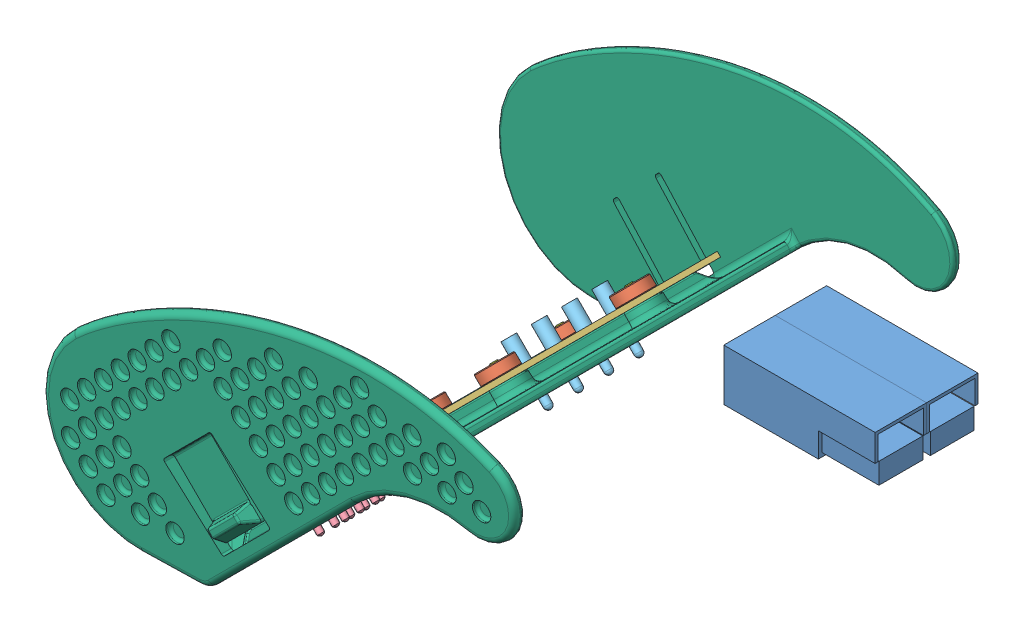
SolidWorks assembly AU-SK-2-000669, configuration Default. Lengths in mm.
Overall size (144.45 131.85 147.55).
25 component instances, 9 part files, 24 mates.
Components (placement in the parent):
- AU-SK-100-000494-1: AU-SK-100-000494 [Default] at (-11.8083 -137.0825 45.0576) size (144.45 105.44 132.78)
  - AU-SK-1-000249-1: AU-SK-1-000249 [Default] at (90.6703 82.4308 -22.9944) x (0 0 1) z (-1 -0.00005 0) size (17.27 8.64 25.4)
  - AU-SK-1-000615-1: AU-SK-1-000615 [Default] at (55.9151 53.7792 -42.3665) size (54 22.81 0.51)
  - AU-SK-1-000614-1: AU-SK-1-000614 [Default] at (56.8933 45.7752 -44.5778) size (52.76 21.32 0.51)
  - AU-SK-1-000592-1: AU-SK-1-000592 [95117A411] at (18.1101 50.4596 -56.7407) x (0.5 0.5 0.707107) z (-0.707107 0.707107 0) size (5.59 5.59 3.59)
  - AU-SK-1-000592-2: AU-SK-1-000592 [95117A411] at (6.4358 38.7852 -56.7407) x (0.5 0.5 0.707107) z (-0.707107 0.707107 0) size (5.59 5.59 3.59)
  - AU-SK-1-000592-3: AU-SK-1-000592 [95117A411] at (18.1101 50.4596 -34.0839) x (0.5 0.5 0.707107) z (-0.707107 0.707107 0) size (5.59 5.59 3.59)
  - AU-SK-1-000592-4: AU-SK-1-000592 [95117A411] at (6.4358 38.7852 -34.0839) x (0.5 0.5 0.707107) z (-0.707107 0.707107 0) size (5.59 5.59 3.59)
  - AU-SK-1-000592-5: AU-SK-1-000592 [95117A411] at (18.1101 50.4596 -11.4271) x (0.5 0.5 0.707107) z (-0.707107 0.707107 0) size (5.59 5.59 3.59)
  - AU-SK-1-000592-6: AU-SK-1-000592 [95117A411] at (6.4358 38.7852 -11.4271) x (0.5 0.5 0.707107) z (-0.707107 0.707107 0) size (5.59 5.59 3.59)
  - AU-SK-2-000791-1: AU-SK-2-000791 [Default] at (29.3531 69.1902 -54.4746) size (81.07 81.07 132.78)
    - AU-SK-1-000449-1: AU-SK-1-000449 [Default] at (-82.5713 -93.6909 -83.1375) x (0 0 1) z (-0.707107 0.707107 0) size (132.78 113.86 0.79)
    - AU-SK-1-000590-1: AU-SK-1-000590 [Default] at (-11.8156 -27.4433 32.3933) x (0 0 -1) z (-0.707107 -0.707107 0) size (20.32 6.76 2.54)
    - AU-SK-1-000080-1: AU-SK-1-000080 [Default] at (-18.3223 -23.3313 -4.3851) x (0.658834 0.658834 -0.363148) z (-0.256784 -0.256784 -0.931732) size (3.81 9.91 3.81)
    - AU-SK-1-000080-2: AU-SK-1-000080 [Default] at (-18.3203 -23.3333 0.6949) x (-0.707107 -0.707107 0) z (0 0 1) size (3.81 9.91 3.81)
    - AU-SK-1-000080-3: AU-SK-1-000080 [Default] at (-18.3203 -23.3333 5.7749) x (-0.707107 -0.707107 0) z (0 0 1) size (3.81 9.91 3.81)
    - AU-SK-1-000080-4: AU-SK-1-000080 [Default] at (-18.3203 -23.3333 10.8549) x (-0.707107 -0.707107 0) z (0 0 1) size (3.81 9.91 3.81)
    - AU-SK-1-000590-2: AU-SK-1-000590 [Default] at (-16.0064 -31.6341 32.3933) x (0 0 -1) z (-0.707107 -0.707107 0) size (20.32 6.76 2.54)
- AU-SK-1-000474-1: AU-SK-1-000474 [Default] at (-3.9 -105.7731 10.9669) x (0 0 1) z (-0.707107 0.707107 0) size (87.74 80.21 52.37)
- AU-SK-1-000591-1: AU-SK-1-000591 [91253A078] at (6.1961 -86.5172 -11.6831) x (0.5 0.5 0.707107) z (-0.707107 0.707107 0) size (5 5 6.82)
- AU-SK-1-000591-2: AU-SK-1-000591 [91253A078] at (6.1961 -86.5172 33.6169) x (0.5 0.5 0.707107) z (-0.707107 0.707107 0) size (5 5 6.82)
- AU-SK-1-000591-3: AU-SK-1-000591 [91253A078] at (-5.4783 -98.1915 -11.6831) x (0.5 0.5 0.707107) z (-0.707107 0.707107 0) size (5 5 6.82)
- AU-SK-1-000591-4: AU-SK-1-000591 [91253A078] at (-5.4783 -98.1915 33.6169) x (0.5 0.5 0.707107) z (-0.707107 0.707107 0) size (5 5 6.82)
- AU-SK-1-000591-5: AU-SK-1-000591 [91253A078] at (-5.4348 -98.2349 10.9669) x (0.5 0.5 0.707107) z (-0.707107 0.707107 0) size (5 5 6.82)
- AU-SK-1-000591-6: AU-SK-1-000591 [91253A078] at (6.1961 -86.5172 10.9669) x (0.5 0.5 0.707107) z (-0.707107 0.707107 0) size (5 5 6.82)
Mates (geometry in assembly coordinates):
- Concentric3: concentric: circle of AU-SK-1-000474-1; circle of AU-SK-100-000494-1/AU-SK-2-000791-1/AU-SK-1-000080-1
- Coincident69: coincident: plane of AU-SK-1-000474-1 through (-6.5582 -103.1149 10.9669) normal (-0.707107 0.707107 0); plane of ? through (-31.2723 -127.8291 10.9669) normal (0.707107 -0.707107 0)
- Concentric19: concentric: circle of AU-SK-1-000474-1; circle of ?
- Concentric20: concentric: circle of AU-SK-1-000474-1; circle of ?
- Concentric21: concentric: circle of AU-SK-1-000474-1; circle of AU-SK-100-000494-1/AU-SK-2-000791-1/AU-SK-1-000590-1
- Parallel18: parallel: line of AU-SK-1-000474-1 through (4.9112 -94.7168 18.4559) axis (0 0 1); plane of AU-SK-100-000494-1/AU-SK-2-000791-1/AU-SK-1-000590-1 through (3.7536 -93.36 22.9763) normal (-0.707107 -0.707107 0)
- Concentric18: concentric: circle of AU-SK-100-000494-1/AU-SK-1-000592-1; circle of AU-SK-1-000591-1
- Distance10: distance = 0.127 mm: plane of AU-SK-1-000591-1 through (10.6862 -91.0073 -11.6831) normal (0.707107 -0.707107 0); plane of AU-SK-1-000474-1 through (20.8487 -81.0244 48.9399) normal (0.707107 -0.707107 0)
- Concentric22: concentric anti-aligned: circle of AU-SK-1-000474-1; circle of AU-SK-1-000591-6
- Concentric23: concentric aligned: circle of AU-SK-1-000591-2; circle of AU-SK-1-000474-1
- Concentric24: concentric anti-aligned: circle of AU-SK-1-000474-1; circle of AU-SK-1-000591-4
- Concentric25: concentric anti-aligned: circle of AU-SK-1-000474-1; circle of AU-SK-1-000591-5
- Concentric26: concentric anti-aligned: circle of AU-SK-1-000474-1; circle of AU-SK-1-000591-3
- Coincident70: coincident aligned: plane of AU-SK-1-000591-1 through (10.6862 -91.0073 -11.6831) normal (0.707107 -0.707107 0); plane of AU-SK-1-000591-6 through (10.6862 -91.0073 10.9669) normal (0.707107 -0.707107 0)
- Coincident71: coincident aligned: plane of AU-SK-1-000591-1 through (10.6862 -91.0073 -11.6831) normal (0.707107 -0.707107 0); plane of AU-SK-1-000591-2 through (10.6862 -91.0073 33.6169) normal (0.707107 -0.707107 0)
- Coincident72: coincident aligned: plane of AU-SK-1-000591-1 through (10.6862 -91.0073 -11.6831) normal (0.707107 -0.707107 0); plane of AU-SK-1-000591-3 through (-0.9881 -102.6816 -11.6831) normal (0.707107 -0.707107 0)
- Coincident73: coincident anti-aligned: plane of AU-SK-1-000591-1 through (10.6862 -91.0073 -11.6831) normal (0.707107 -0.707107 0); circle of AU-SK-1-000591-5
- Coincident74: coincident aligned: plane of AU-SK-1-000591-1 through (10.6862 -91.0073 -11.6831) normal (0.707107 -0.707107 0); circle of AU-SK-1-000591-4
- Concentric9: concentric: cone of AU-SK-1-000474-1 through (4.936 -96.9371 -8.7221) axis (0.707107 -0.707107 0); cylinder of AU-SK-100-000494-1/AU-SK-2-000791-1/AU-SK-1-000080-2 through (-0.7755 -91.2257 -8.7221) axis (-0.707107 0.707107 0) radius 0.635
- Concentric10: concentric: cone of AU-SK-1-000474-1 through (4.936 -96.9371 -3.6421) axis (0.707107 -0.707107 0); cylinder of AU-SK-100-000494-1/AU-SK-2-000791-1/AU-SK-1-000080-3 through (-0.7755 -91.2257 -3.6421) axis (-0.707107 0.707107 0) radius 0.635
- Concentric11: concentric: cone of AU-SK-1-000474-1 through (4.936 -96.9371 1.4379) axis (0.707107 -0.707107 0); cylinder of AU-SK-100-000494-1/AU-SK-2-000791-1/AU-SK-1-000080-4 through (-0.7755 -91.2257 1.4379) axis (-0.707107 0.707107 0) radius 0.635
- Concentric6: concentric: cone of AU-SK-1-000474-1 through (2.8406 -99.0325 19.4719) axis (0.707107 -0.707107 0); cylinder of AU-SK-100-000494-1/AU-SK-2-000791-1/AU-SK-1-000590-2 through (-1.0658 -95.1261 19.4719) axis (-0.707107 0.707107 0) radius 0.2159
- Concentric8: concentric: cone of AU-SK-1-000474-1 through (2.8406 -99.0325 37.2519) axis (0.707107 -0.707107 0); cylinder of AU-SK-100-000494-1/AU-SK-2-000791-1/AU-SK-1-000590-2 through (1.5923 -97.7842 37.2519) axis (-0.707107 0.707107 0) radius 0.5309
- Coincident104: coincident: plane of AU-SK-1-000474-1 through (1.4487 -99.6162 18.0749) normal (-0.707107 0.707107 0); plane of AU-SK-100-000494-1/AU-SK-2-000791-1/AU-SK-1-000590-2 through (3.3345 -97.7304 33.7476) normal (0.707107 -0.707107 0)
